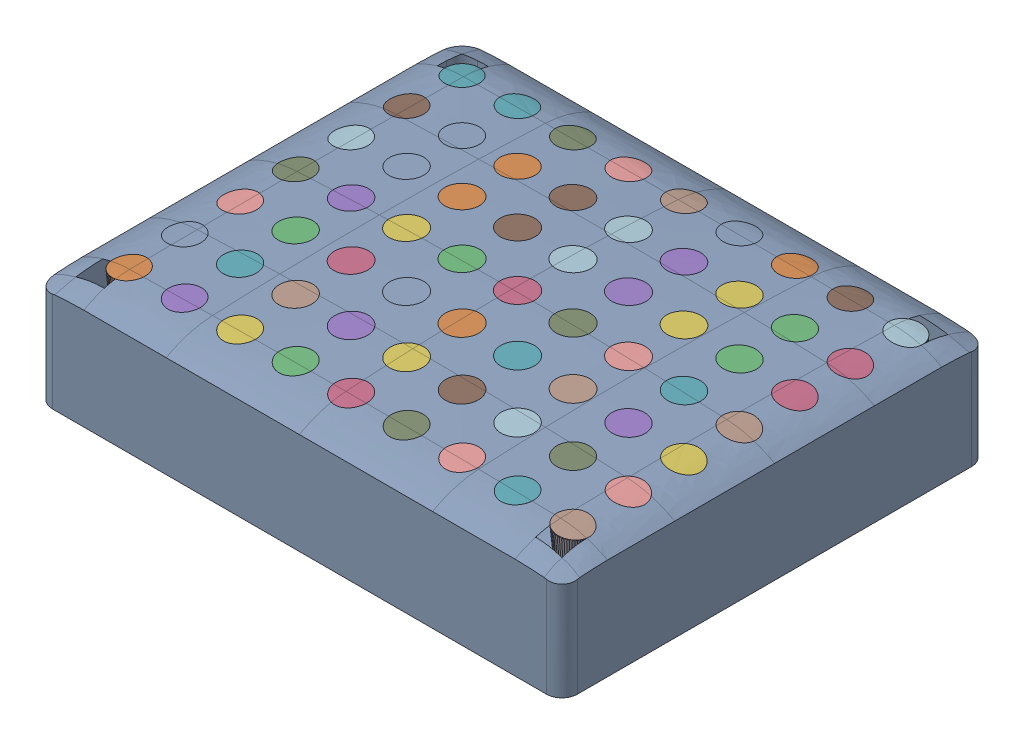
SolidWorks assembly 中间过程, configuration 默认. Lengths in mm.
Overall size (23.8 5.49 19.29).
3 component instances, 3 part files, 5 mates.
Components (placement in the parent):
- InsideSkin-1: InsideSkin [默认] at origin size (23.8 5.49 19.29)
- markerTopTip-1: markerTopTip [默认] at (-10.075 22.5 -8.075) x (1 0 0) z (0 -1 0) size (21.2 16.2 0.4)
- Pinmarker1mm_1-1: Pinmarker1mm_1 [默认] at origin size (21.57 1.99 16.56)
Mates (geometry in assembly coordinates):
- 重合1: coordinate: point of Pinmarker1mm_1-1
- 重合2: coordinate: unknown of InsideSkin-1
- 同心1: concentric anti-aligned: cylinder of markerTopTip-1 through (-10.075 22.1 6.925) axis (0 1 0) radius 0.6; cone of Pinmarker1mm_1-1 through (-10.075 22.5 6.925) axis (0 -1 0)
- 重合3: coincident anti-aligned: plane of markerTopTip-1 through (-10.075 22.5 6.925) normal (0 1 0); plane of Pinmarker1mm_1-1 through (-10.075 22.5 6.925) normal (0 -1 0)
- 同心2: concentric anti-aligned: cylinder of markerTopTip-1 through (-7.575 22.1 6.925) axis (0 1 0) radius 0.6; cone of Pinmarker1mm_1-1 through (-7.575 22.5 6.925) axis (0 -1 0)
